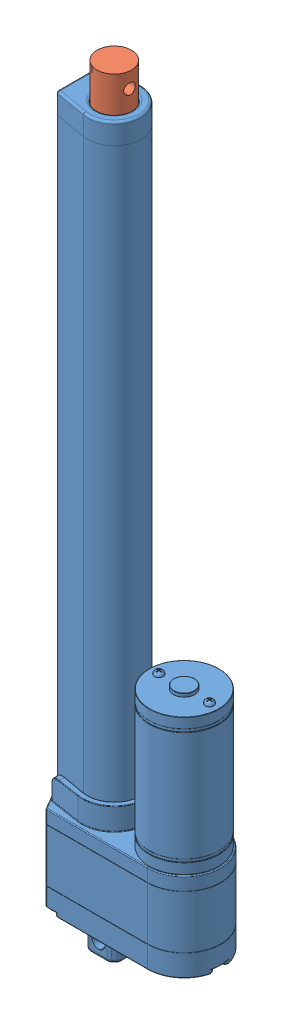
SolidWorks assembly Pololu_Linear_Actuator_FB_12in, configuration Predeterminado. Lengths in mm.
Overall size (84.84 440.4 41.91).
2 component instances, 2 part files, 5 mates.
Components (placement in the parent):
- Pololu_Linear_Actuator_FB_Body_12in-2: Pololu_Linear_Actuator_FB_Body_12in [Predeterminado] at (0 50.8 0) size (84.84 420.62 41.91)
- Pololu_Linear_Actuator_FB_PistonRod_12in-2: Pololu_Linear_Actuator_FB_PistonRod_12in [Predeterminado] at (-40.005 52.8 0) x (-0.072623 0 0.997359) z (-0.997359 0 -0.072623) size (21 369.54 21)
Mates (geometry in assembly coordinates):
- Concéntrica1: concentric aligned: cylinder of Pololu_Linear_Actuator_FB_Body_12in-2 through (-40.005 388.62 0) axis (0 -1 0) radius 9.906; cylinder of Pololu_Linear_Actuator_FB_PistonRod_12in-2 through (-40.005 420.338 0) axis (0 -1 0) radius 9.906
- Distancia límite1: limit distance = 0 mm anti-aligned: plane of Pololu_Linear_Actuator_FB_Body_12in-2 through (0 50.8 0) normal (0 1 0); plane of Pololu_Linear_Actuator_FB_PistonRod_12in-2 through (-40.005 50.8 0) normal (0 -1 0)
- Coincidente2: coincident anti-aligned: plane of Pololu_Linear_Actuator_FB_Body_12in-2 through (0 0 0) normal (0 -1 0)
- Coincidente3: coincident aligned: plane of Pololu_Linear_Actuator_FB_Body_12in-2 through (0 50.8 0) normal (0 0 1)
- Coincidente4: coincident aligned: plane of Pololu_Linear_Actuator_FB_Body_12in-2 through (0 50.8 0) normal (1 0 0)
